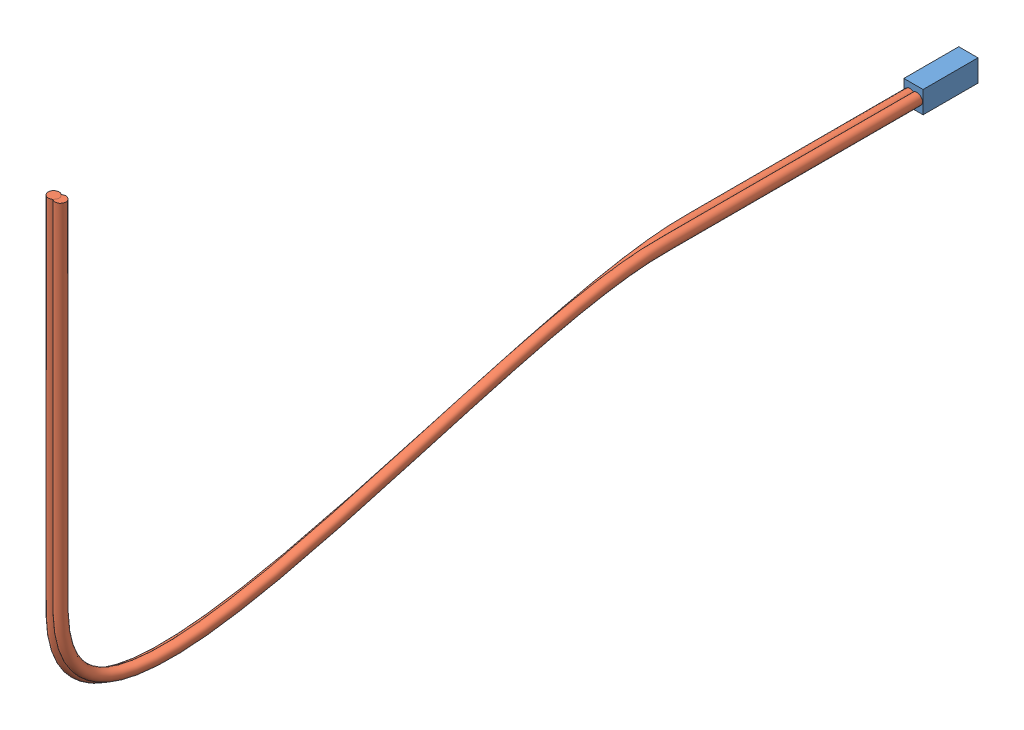
SolidWorks assembly Harness_3-CABLE_HARNESSING_ASSEMBLY, configuration Default. Lengths in mm.
Overall size (25.15 80.44 147.65).
3 component instances, 3 part files, 0 mates.
Components (placement in the parent):
- 02_PIN-1: 02_PIN [Default] at (2.0703 9.5684 -141.1129) size (3.5 4 20)
- Cable^Harness_3-CABLE_HARNESSING_ASSEMBLY-1: Cable^Harness_3-CABLE_HARNESSING_ASSEMBLY [Default] at origin size (25.15 80.44 138.4) (virtual)
- Flattened_Cable^Harness_3-CABLE_HARNESSING_ASSEMBLY-1: Flattened_Cable^Harness_3-CABLE_HARNESSING_ASSEMBLY [Default] at origin (suppressed, hidden, virtual)
